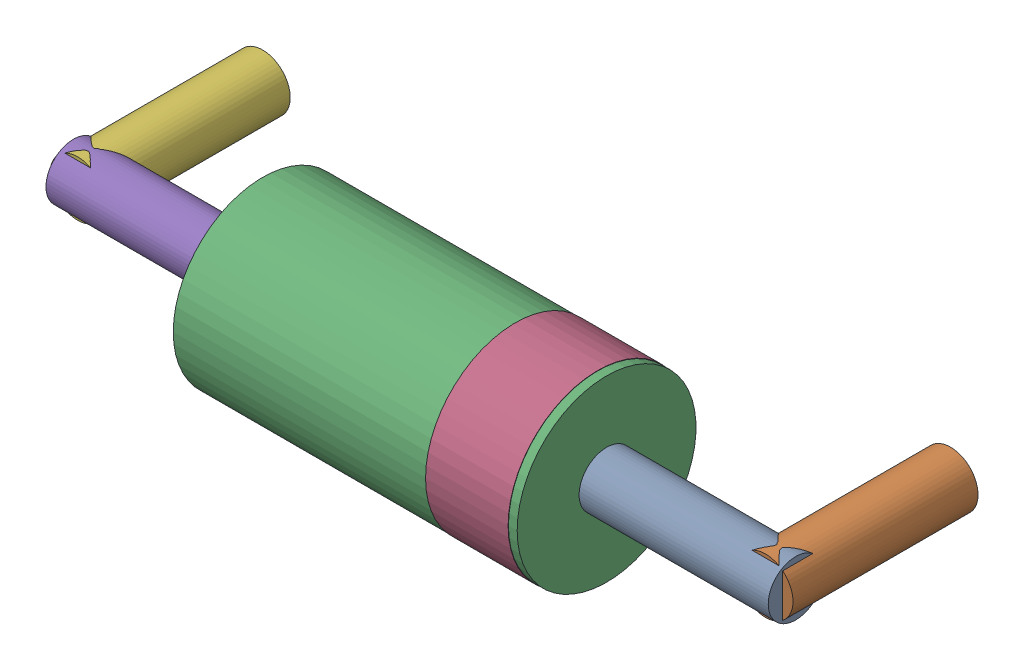
SolidWorks assembly D5, configuration Default. Lengths in mm.
Overall size (10.8 2.61 3.81).
12 component instances, 6 part files, 0 mates.
Components (placement in the parent):
- -1733042672-1: -1733042672 [Default] at (501.2503 261.9977 1.5) x (0 0 -1) z (-1 0 0) size (0.8 0.8 2.75)
  - Cylinder-1: Cylinder [Default] at origin size (0.8 0.8 2.75)
- -1733042992-1: -1733042992 [Default] at (500.9999 261.9999 -1) x (-1 0 0) z (0 0 1) size (0.8 0.8 2.69)
  - Cylinder_2-1: Cylinder_2 [Default] at origin size (0.8 0.8 2.69)
- -1733042432-1: -1733042432 [Default] at (498.5001 261.9975 1.5) x (0 0 -1) z (-1 0 0) size (2.6 2.6 5)
  - Cylinder_3-1: Cylinder_3 [Default] at origin size (2.6 2.6 5)
- -1733042152-1: -1733042152 [Default] at (498.3731 261.9976 1.5) x (0 0 -1) z (-1 0 0) size (2.61 2.61 1.2)
  - Cylinder_4-1: Cylinder_4 [Default] at origin size (2.61 2.61 1.2)
- -1733041072-1: -1733041072 [Default] at (490.7497 262.0023 1.5) x (0 0 -1) z (1 0 0) size (0.8 0.8 2.75)
  - Cylinder_5-1: Cylinder_5 [Default] at origin size (0.8 0.8 2.75)
- -1733041192-1: -1733041192 [Default] at (491.0001 262.0001 -1) x (1 0 0) z (0 0 1) size (0.8 0.8 2.69)
  - Cylinder_6-1: Cylinder_6 [Default] at origin size (0.8 0.8 2.69)
